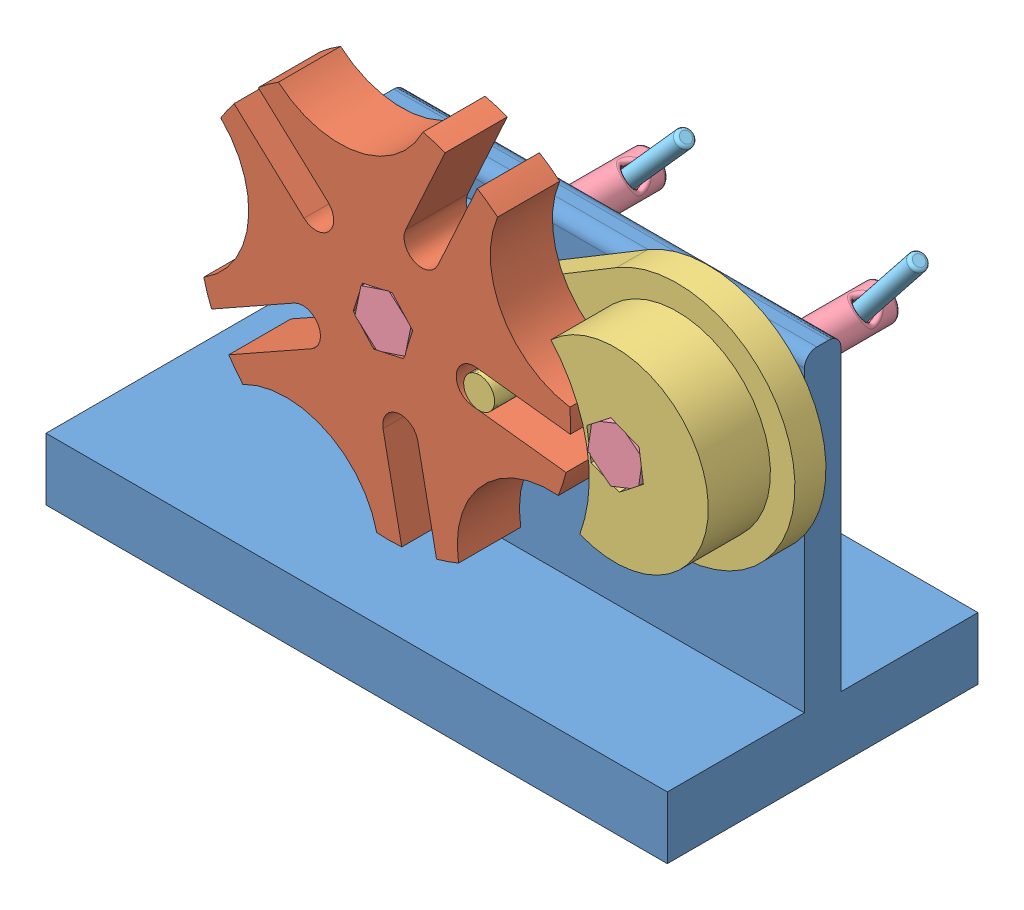
SolidWorks assembly GenevaGearAssembly, configuration Default. Lengths in mm.
Overall size (109.54 79.02 50.06).
7 component instances, 5 part files, 14 mates.
Components (placement in the parent):
- Base5Sides-1: Base5Sides [Default] at (-66.9775 -55.0517 40.1795) size (100 60 50)
- GenevaGear5Sides-1: GenevaGear5Sides [Default] at (-62.899 -9.3378 59.8717) x (0.979079 0.203481 0) z (0 0 -1) size (60 57.81 10)
- GearDriver5Sides-1: GearDriver5Sides [Default] at (-24.664 -6.7371 44.8717) x (0.405833 -0.913947 0) z (0 0 1) size (37.88 48.63 15)
- Crank5Sides-1: Crank5Sides [Default] at (-27.3761 -11.7118 56.8717) x (-0.783402 0.621516 0) z (0 0 1) size (9.5 8.23 43)
- Crank5Sides-2: Crank5Sides [Default] at (-60.9299 -7.0726 56.8717) x (0.746589 -0.665285 0) z (0 0 1) size (9.5 8.23 43)
- Pin-1: Pin [Default] at (-34.0802 -20.1014 21.0448) x (0.621516 0.783402 0) z (0.001521 -0.001207 0.999998) size (30 2.7 2.7)
- Pin-2: Pin [Default] at (-52.9524 1.8232 21.0448) x (-0.665285 -0.746589 0) z (-0.718014 0.639821 0.274017) size (30 2.7 2.7)
Mates (geometry in assembly coordinates):
- Coincident2: coincident anti-aligned: plane of Base5Sides-1 through (-66.9775 4.9483 44.8717) normal (0 0 1); plane of GearDriver5Sides-1 through (-24.664 -6.7371 44.8717) normal (0 0 -1)
- Concentric1: concentric anti-aligned: cylinder of GearDriver5Sides-1 through (-25.5398 -9.3378 59.8717) axis (0 0 -1) radius 3; cylinder of Crank5Sides-1 through (-25.5398 -9.3378 16.8717) axis (0 0 1) radius 2.85
- Concentric2: concentric anti-aligned: cylinder of Base5Sides-1 through (-25.5398 -9.3378 54.8717) axis (0 0 -1) radius 3; cylinder of Crank5Sides-1 through (-25.5398 -9.3378 16.8717) axis (0 0 1) radius 2.85
- Coincident6: coincident anti-aligned: plane of GenevaGear5Sides-1 through (-62.899 -9.3378 49.8717) normal (0 0 -1); plane of GearDriver5Sides-1 through (-24.664 -6.7371 49.8717) normal (0 0 1)
- Coincident7: coincident anti-aligned: plane of GenevaGear5Sides-1 through (-62.899 -9.3378 49.8717) normal (0 0 -1); plane of GearDriver5Sides-1 through (-24.664 -6.7371 49.8717) normal (0 0 1)
- Concentric3: concentric anti-aligned: cylinder of Base5Sides-1 through (-62.899 -9.3378 54.8717) axis (0 0 -1) radius 3; cylinder of GenevaGear5Sides-1 through (-62.899 -9.3378 49.8717) axis (0 0 1) radius 3
- Concentric4: concentric aligned: cylinder of GenevaGear5Sides-1 through (-62.899 -9.3378 49.8717) axis (0 0 1) radius 3; cylinder of Crank5Sides-2 through (-62.899 -9.3378 16.8717) axis (0 0 1) radius 2.85
- Coincident9: coincident anti-aligned: plane of GenevaGear5Sides-1 through (-62.899 -9.3378 56.8717) normal (0 0 1); plane of Crank5Sides-2 through (-60.9299 -7.0726 56.8717) normal (0 0 -1)
- Concentric5: concentric anti-aligned: cylinder of Crank5Sides-1 through (-33.6208 -19.5224 21.0448) axis (0.621516 0.783402 0) radius 1.5; cylinder of Pin-1 through (-15.4347 3.4006 21.0448) axis (-0.621516 -0.783402 0) radius 1.35
- Lock1: lock: unknown of Crank5Sides-1; unknown of Pin-1
- Concentric7: concentric anti-aligned: cylinder of Crank5Sides-2 through (-54.2489 0.3682 21.0448) axis (-0.665285 -0.746589 0) radius 1.5; cylinder of Pin-2 through (-72.9109 -20.5745 21.0448) axis (0.665285 0.746589 0) radius 1.35
- Lock3: lock: unknown of Crank5Sides-2; unknown of Pin-2
- Tangent2: tangent anti-aligned: plane of GenevaGear5Sides-1 through (-63.2395 -12.2742 49.8717) normal (0.115208 0.993341 0); cylinder of GearDriver5Sides-1 through (-47.4224 -11.592 59.8717) axis (0 0 -1) radius 2.5
- Coincident13: coincident anti-aligned: plane of GearDriver5Sides-1 through (-24.664 -6.7371 56.8717) normal (0 0 1); plane of Crank5Sides-1 through (-27.3761 -11.7118 56.8717) normal (0 0 -1)
